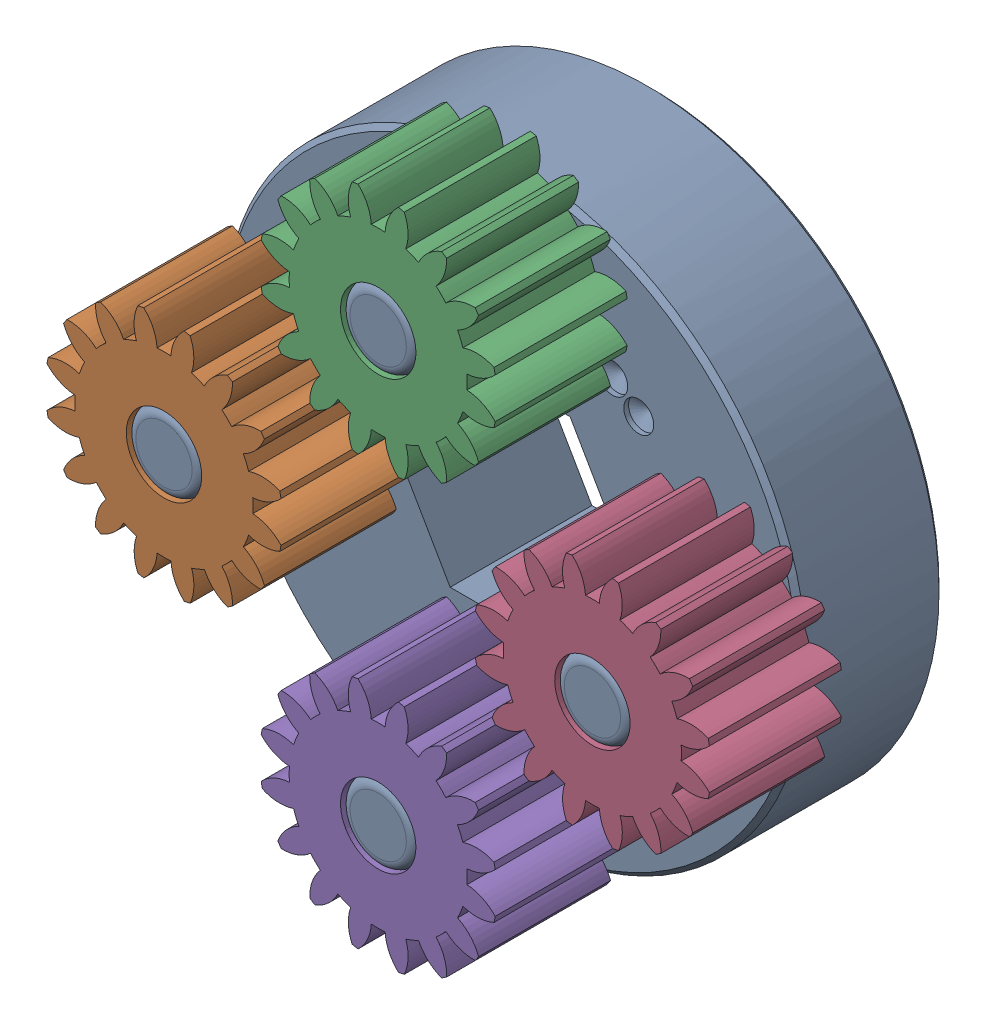
SolidWorks assembly 4_1 Output Stage, configuration Default. Lengths in mm.
Overall size (38.96 38.96 14.52).
5 component instances, 2 part files, 0 mates.
Components (placement in the parent):
- 4_1 Output Stage Carrier Plate-1: 4_1 Output Stage Carrier Plate [Default] at (-141.4265 -4.3625 67.1279) size (30.99 30.99 14.52)
- 16T Short Planet Gear-1: 16T Short Planet Gear [Default] at (-155.2063 -5.4237 83.0693) x (0 0 1) z (0.923728 0.383049 0) size (7 12.42 12.42)
- 16T Short Planet Gear-2: 16T Short Planet Gear [Default] at (-142.4877 9.4173 83.0693) x (0 0 1) z (0.383049 -0.923728 0) size (7 12.42 12.42)
- 16T Short Planet Gear-3: 16T Short Planet Gear [Default] at (-127.6467 -3.3013 83.0693) x (0 0 1) z (-0.923728 -0.383049 0) size (7 12.42 12.42)
- 16T Short Planet Gear-4: 16T Short Planet Gear [Default] at (-140.3653 -18.1423 83.0693) x (0 0 1) z (-0.383049 0.923728 0) size (7 12.42 12.42)
